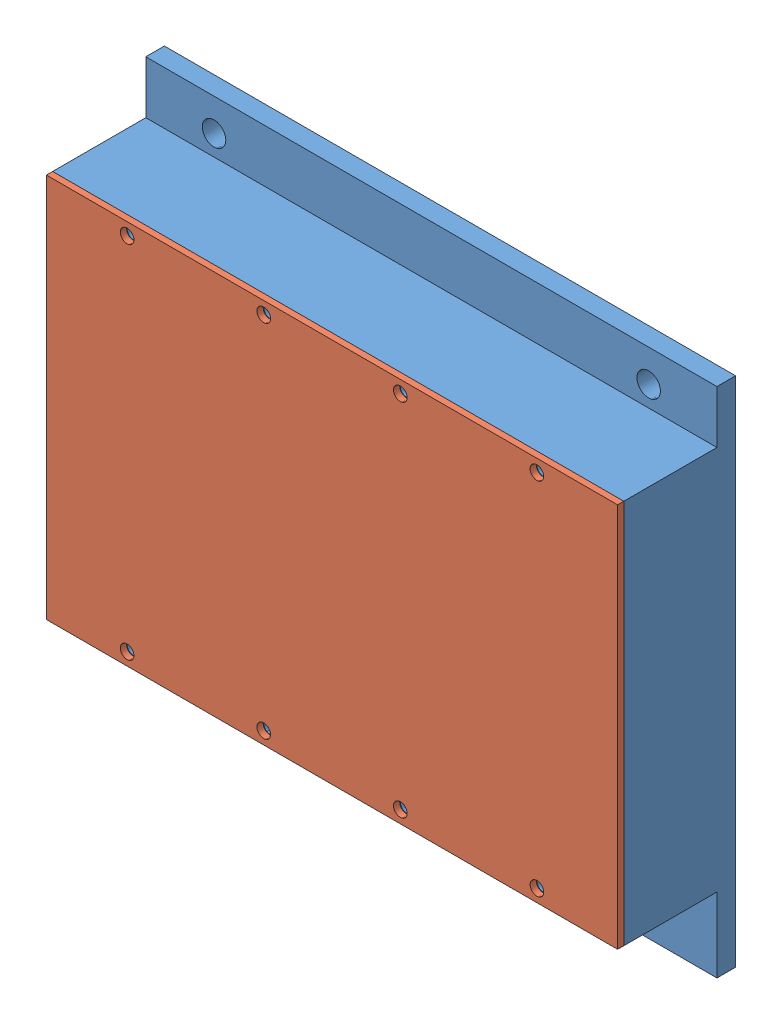
SolidWorks assembly B3_battery, configuration Default. Lengths in mm.
Overall size (92 82.5 20.29).
14 component instances, 6 part files, 40 mates.
Components (placement in the parent):
- B3_battery_case-1: B3_battery_case [Default] at (-27.6193 12.9444 0.2286) size (92 82.5 18)
- B3_battery_cover-1: B3_battery_cover [Default] at (-73.6193 43.9444 18.2286) size (92 62 1)
- B3_battery_insulator1-1: B3_battery_insulator1 [Default] at (-29.6748 38.9444 -2.4068) x (1 0 0) z (0 1 0) size (88.4 17 1)
- B3_battery_insulator1-2: B3_battery_insulator1 [Default] at (-25.5639 -14.0556 19.864) x (-1 0 0) z (0 1 0) size (88.4 17 1)
- B3_battery_insulator2-1: B3_battery_insulator2 [Default] at (15.5807 9.9046 1.8438) x (0 -1 0) z (0 0 1) size (52 1 17)
- B3_battery_insulator2-3: B3_battery_insulator2 [Default] at (-71.8193 9.9046 1.8438) x (0 -1 0) z (0 0 1) size (52 1 17)
- B3_battery_insulator3-1: B3_battery_insulator3 [Default] at (-40.702 30.9956 0.2286) x (1 0 0) z (0 -1 0) size (86.4 1 52)
- battery-8: battery [Default] at (-63.3443 -13.0556 8.4036) x (-0.702082 0 -0.712097) z (0.712097 0 -0.702082) size (14.35 52 14.35)
- battery-9: battery [Default] at (-48.9943 -13.0556 8.4036) x (-0.963236 0 -0.268658) z (0.268658 0 -0.963236) size (14.35 52 14.35)
- battery-10: battery [Default] at (-34.6443 -13.0556 8.4036) x (-0.96243 0 -0.271529) z (0.271529 0 -0.96243) size (14.35 52 14.35)
- battery-11: battery [Default] at (-20.2943 -13.0556 8.4036) x (0.998572 0 0.05343) z (-0.05343 0 0.998572) size (14.35 52 14.35)
- battery-12: battery [Default] at (-5.9443 -13.0556 8.4036) x (-0.654063 0 0.75644) z (-0.75644 0 -0.654063) size (14.35 52 14.35)
- battery-14: battery [Default] at (8.4057 -13.0556 8.4036) x (0.87582 0 0.482638) z (-0.482638 0 0.87582) size (14.35 52 14.35)
- B3_battery_insulator3-2: B3_battery_insulator3 [Default] at (-40.702 30.9956 15.5786) x (1 0 0) z (0 -1 0) size (86.4 1 52) (hidden)
Mates (geometry in assembly coordinates):
- Coincident13: coincident aligned: plane of B3_battery_insulator1-1 through (-71.8193 39.9444 17.2286) normal (0 0 1); plane of B3_battery_insulator1-2 through (16.5807 -13.0556 17.2286) normal (0 0 1)
- Coincident26: coincident anti-aligned: plane of B3_battery_insulator1-1 through (-29.6748 38.9444 -2.4068) normal (0 -1 0); plane of B3_battery_insulator2-1 through (16.5807 38.9444 0.2286) normal (0 1 0)
- Coincident29: coincident anti-aligned: plane of B3_battery_insulator1-1 through (-29.6748 38.9444 -2.4068) normal (0 -1 0); plane of B3_battery_insulator2-3 through (-70.8193 38.9444 0.2286) normal (0 1 0)
- Tangent30: tangent anti-aligned: plane of B3_battery_insulator2-1 through (15.5807 9.9046 1.8438) normal (-1 0 0); cylinder of battery-14 through (8.4057 37.9444 8.4036) axis (0 -1 0) radius 7.175
- Coincident46: coincident anti-aligned: plane of B3_battery_insulator1-2 through (-25.5639 -13.0556 19.864) normal (0 1 0); plane of battery-14 through (8.4057 -13.0556 8.4036) normal (0 -1 0)
- Coincident47: coincident anti-aligned: plane of B3_battery_insulator1-2 through (-25.5639 -13.0556 19.864) normal (0 1 0); plane of battery-12 through (-5.9443 -13.0556 8.4036) normal (0 -1 0)
- Tangent32: tangent anti-aligned: cylinder of battery-12 through (-5.9443 37.9444 8.4036) axis (0 -1 0) radius 7.175; cylinder of battery-14 through (8.4057 37.9444 8.4036) axis (0 -1 0) radius 7.175
- Coincident48: coincident anti-aligned: plane of B3_battery_insulator1-2 through (-25.5639 -13.0556 19.864) normal (0 1 0); plane of battery-11 through (-20.2943 -13.0556 8.4036) normal (0 -1 0)
- Tangent34: tangent anti-aligned: cylinder of battery-11 through (-20.2943 37.9444 8.4036) axis (0 -1 0) radius 7.175; cylinder of battery-12 through (-5.9443 37.9444 8.4036) axis (0 -1 0) radius 7.175
- Coincident49: coincident anti-aligned: plane of B3_battery_insulator1-2 through (-25.5639 -13.0556 19.864) normal (0 1 0); plane of battery-10 through (-34.6443 -13.0556 8.4036) normal (0 -1 0)
- Tangent36: tangent anti-aligned: cylinder of battery-10 through (-34.6443 37.9444 8.4036) axis (0 -1 0) radius 7.175; cylinder of battery-11 through (-20.2943 37.9444 8.4036) axis (0 -1 0) radius 7.175
- Coincident50: coincident anti-aligned: plane of B3_battery_insulator1-2 through (-25.5639 -13.0556 19.864) normal (0 1 0); plane of battery-9 through (-48.9943 -13.0556 8.4036) normal (0 -1 0)
- Tangent38: tangent anti-aligned: cylinder of battery-9 through (-48.9943 37.9444 8.4036) axis (0 -1 0) radius 7.175; cylinder of battery-10 through (-34.6443 37.9444 8.4036) axis (0 -1 0) radius 7.175
- Coincident51: coincident anti-aligned: plane of B3_battery_insulator1-2 through (-25.5639 -13.0556 19.864) normal (0 1 0); plane of battery-8 through (-63.3443 -13.0556 8.4036) normal (0 -1 0)
- Tangent40: tangent anti-aligned: cylinder of battery-8 through (-63.3443 37.9444 8.4036) axis (0 -1 0) radius 7.175; cylinder of battery-9 through (-48.9943 37.9444 8.4036) axis (0 -1 0) radius 7.175
- Coincident52: coincident anti-aligned: plane of B3_battery_insulator2-1 through (15.5807 9.9046 1.8438) normal (-1 0 0); plane of B3_battery_insulator3-2 through (15.5807 38.9444 16.5786) normal (1 0 0)
- Tangent44: tangent anti-aligned: cylinder of battery-10 through (-34.6443 37.9444 8.4036) axis (0 -1 0) radius 7.175; plane of B3_battery_insulator3-2 through (-40.702 30.9956 15.5786) normal (0 0 -1)
- Coincident53: coincident anti-aligned: plane of B3_battery_insulator1-1 through (-29.6748 38.9444 -2.4068) normal (0 -1 0); plane of B3_battery_insulator3-2 through (-70.8193 38.9444 16.5786) normal (0 1 0)
- 一致11: coincident anti-aligned: plane of B3_battery_case-1 through (-27.6193 12.9444 0.2286) normal (0 0 1); plane of B3_battery_insulator3-1 through (-40.702 30.9956 0.2286) normal (0 0 -1)
- 一致13: coincident anti-aligned: plane of B3_battery_insulator2-3 through (-70.8193 9.9046 1.8438) normal (1 0 0); plane of B3_battery_insulator3-1 through (-70.8193 38.9444 1.2286) normal (-1 0 0)
- 一致14: coincident aligned: plane of B3_battery_insulator2-3 through (-70.8193 -13.0556 0.2286) normal (0 -1 0); plane of B3_battery_insulator3-1 through (-70.8193 -13.0556 1.2286) normal (0 -1 0)
- 一致15: coincident anti-aligned: plane of B3_battery_insulator2-1 through (15.5807 9.9046 1.8438) normal (-1 0 0); plane of B3_battery_insulator3-1 through (15.5807 38.9444 1.2286) normal (1 0 0)
- 一致16: coincident aligned: plane of B3_battery_insulator2-1 through (16.5807 38.9444 0.2286) normal (0 0 -1); plane of B3_battery_insulator3-1 through (-40.702 30.9956 0.2286) normal (0 0 -1)
- 一致17: coincident aligned: plane of B3_battery_insulator1-1 through (-71.8193 39.9444 0.2286) normal (-1 0 0); plane of B3_battery_insulator2-3 through (-71.8193 9.9046 1.8438) normal (-1 0 0)
- 一致18: coincident anti-aligned: plane of B3_battery_insulator1-2 through (-25.5639 -13.0556 19.864) normal (0 1 0); plane of B3_battery_insulator2-3 through (-70.8193 -13.0556 0.2286) normal (0 -1 0)
- 一致19: coincident aligned: plane of B3_battery_insulator2-3 through (-70.8193 38.9444 0.2286) normal (0 0 -1); plane of B3_battery_insulator3-1 through (-40.702 30.9956 0.2286) normal (0 0 -1)
- 一致20: coincident aligned: plane of B3_battery_insulator1-2 through (-71.8193 -13.0556 17.2286) normal (-1 0 0); plane of B3_battery_insulator2-3 through (-71.8193 9.9046 1.8438) normal (-1 0 0)
- 一致21: coincident aligned: plane of B3_battery_insulator1-2 through (16.5807 -13.0556 17.2286) normal (0 0 1); plane of B3_battery_insulator2-3 through (-70.8193 38.9444 17.2286) normal (0 0 1)
- 正接1: tangent anti-aligned: plane of B3_battery_insulator3-1 through (-40.702 30.9956 1.2286) normal (0 0 1); cylinder of battery-14 through (8.4057 37.9444 8.4036) axis (0 -1 0) radius 7.175
- 正接4: tangent anti-aligned: plane of B3_battery_insulator3-1 through (-40.702 30.9956 1.2286) normal (0 0 1); cylinder of battery-12 through (-5.9443 37.9444 8.4036) axis (0 -1 0) radius 7.175
- 正接6: tangent anti-aligned: plane of B3_battery_insulator3-1 through (-40.702 30.9956 1.2286) normal (0 0 1); cylinder of battery-11 through (-20.2943 37.9444 8.4036) axis (0 -1 0) radius 7.175
- 正接7: tangent anti-aligned: plane of B3_battery_insulator3-1 through (-40.702 30.9956 1.2286) normal (0 0 1); cylinder of battery-10 through (-34.6443 37.9444 8.4036) axis (0 -1 0) radius 7.175
- 正接8: tangent anti-aligned: plane of B3_battery_insulator3-1 through (-40.702 30.9956 1.2286) normal (0 0 1); cylinder of battery-9 through (-48.9943 37.9444 8.4036) axis (0 -1 0) radius 7.175
- 正接9: tangent anti-aligned: plane of B3_battery_insulator3-1 through (-40.702 30.9956 1.2286) normal (0 0 1); cylinder of battery-8 through (-63.3443 37.9444 8.4036) axis (0 -1 0) radius 7.175
- 一致22: coincident anti-aligned: plane of B3_battery_case-1 through (-27.6193 12.9444 0.2286) normal (0 0 1); plane of B3_battery_insulator3-1 through (-40.702 30.9956 0.2286) normal (0 0 -1)
- 一致23: coincident anti-aligned: plane of B3_battery_case-1 through (-71.8193 39.9444 17.2286) normal (1 0 0); plane of B3_battery_insulator2-3 through (-71.8193 9.9046 1.8438) normal (-1 0 0)
- 一致24: coincident anti-aligned: plane of B3_battery_case-1 through (16.5807 -14.0556 17.2286) normal (0 1 0); plane of B3_battery_insulator1-2 through (-25.5639 -14.0556 19.864) normal (0 -1 0)
- 一致25: coincident anti-aligned: plane of B3_battery_case-1 through (-27.6193 12.9444 17.2286) normal (0 0 1); plane of B3_battery_cover-1 through (-73.6193 43.9444 17.2286) normal (0 0 -1)
- 一致26: coincident aligned: plane of B3_battery_case-1 through (-73.6193 43.9444 17.2286) normal (-1 0 0); plane of B3_battery_cover-1 through (-73.6193 43.9444 17.2286) normal (-1 0 0)
- 一致27: coincident aligned: plane of B3_battery_case-1 through (18.3807 43.9444 17.2286) normal (0 1 0); plane of B3_battery_cover-1 through (-73.6193 43.9444 17.2286) normal (0 1 0)
